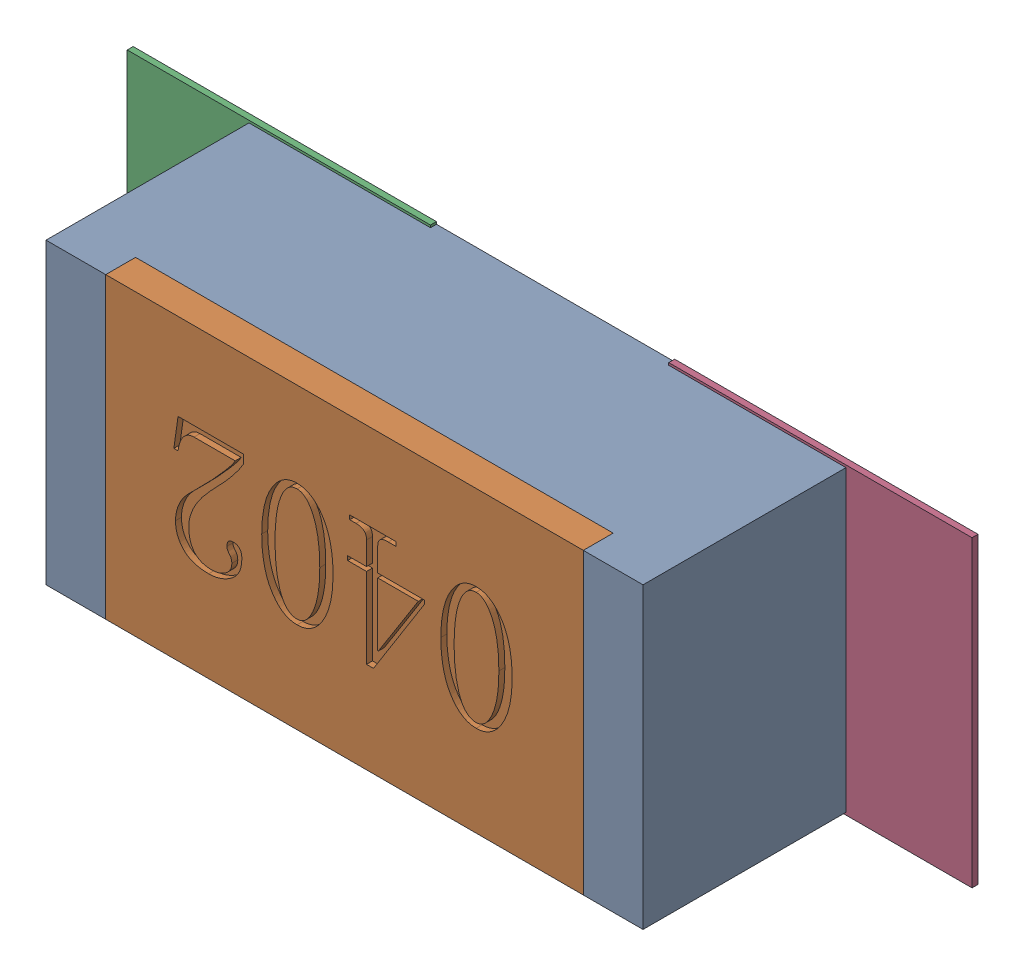
SolidWorks assembly R109, configuration Défaut. Lengths in mm.
Overall size (1.42 0.51 0.35).
5 component instances, 2 part files, 0 mates.
Components (placement in the parent):
- R0402-1: R0402 [Défaut] at (64.3128 -14.4779 0) x (-1 0 0) z (0 0 1) size (1 0.5 0.35)
- 6504207776-1: 6504207776 [Défaut] at (63.8628 -14.478 0) size (0.51 0.51 0.01)
  - Extruded-1: Extruded [Défaut] at origin size (0.51 0.51 0.01)
- 6504207776-2: 6504207776 [Défaut] at (64.7699 -14.478 0) size (0.51 0.51 0.01)
  - Extruded-1: Extruded [Défaut] at origin size (0.51 0.51 0.01)
